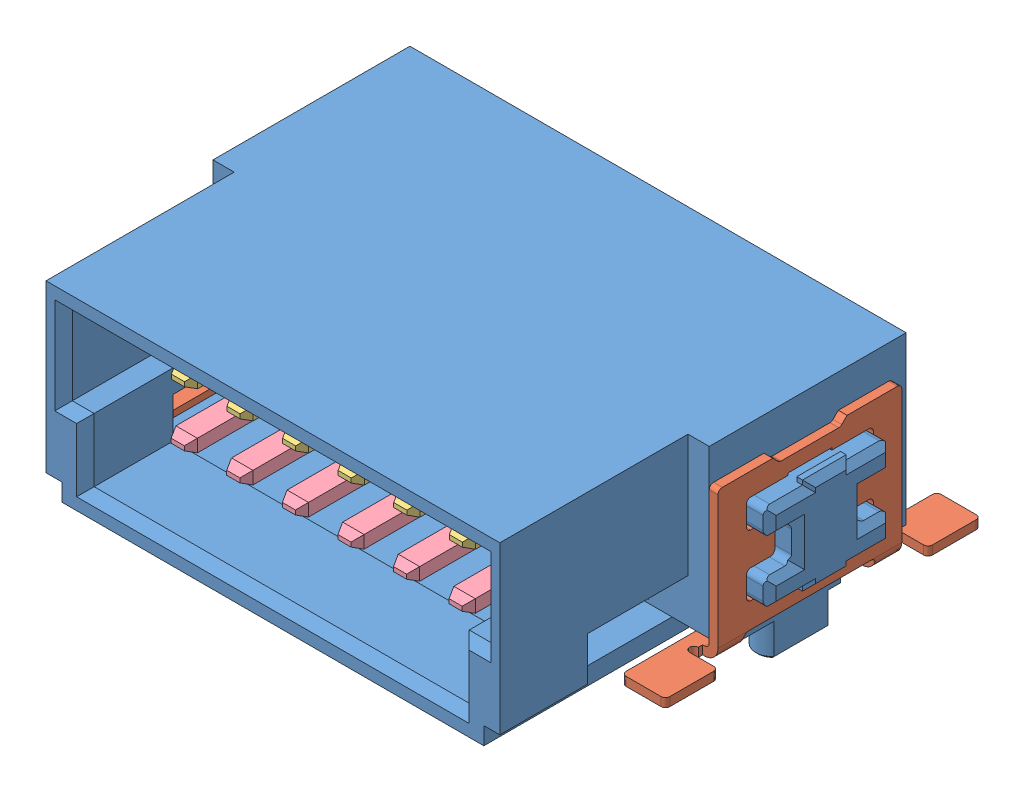
SolidWorks assembly m55-7101242_asm, configuration Default. Lengths in mm.
Overall size (12.7 4.95 10).
16 component instances, 4 part files, 0 mates.
Components (placement in the parent):
- m55-7101242_asm.stp-1: m55-7101242_asm.stp [Default] at origin size (12.7 4.95 10)
  - M55-71012_MOULD.stp-1: M55-71012_MOULD.stp [Default] at origin size (12.7 4.95 8.8)
  - M55-710_STRAP.stp-1: M55-710_STRAP.stp [Default] at (5.67 -2.1 2.4) x (-1 0 0) z (0 0 -1) size (1 3.44 7.2)
  - M55-710_STRAP.stp-2: M55-710_STRAP.stp [Default] at (-5.67 -2.1 2.4) size (1 3.44 7.2)
  - M55-710_LARGE_CONTACT.stp-1: M55-710_LARGE_CONTACT.stp [Default] at (-3.17 0.635 3.6) x (1 0 0) z (0 -1 0) size (1.1 9 2.88)
  - M55-710_LARGE_CONTACT.stp-2: M55-710_LARGE_CONTACT.stp [Default] at (-1.9 0.635 3.6) x (1 0 0) z (0 -1 0) size (1.1 9 2.88)
  - M55-710_LARGE_CONTACT.stp-3: M55-710_LARGE_CONTACT.stp [Default] at (-0.63 0.635 3.6) x (1 0 0) z (0 -1 0) size (1.1 9 2.88)
  - M55-710_LARGE_CONTACT.stp-4: M55-710_LARGE_CONTACT.stp [Default] at (0.64 0.635 3.6) x (1 0 0) z (0 -1 0) size (1.1 9 2.88)
  - M55-710_LARGE_CONTACT.stp-5: M55-710_LARGE_CONTACT.stp [Default] at (1.91 0.635 3.6) x (1 0 0) z (0 -1 0) size (1.1 9 2.88)
  - M55-710_LARGE_CONTACT.stp-6: M55-710_LARGE_CONTACT.stp [Default] at (3.18 0.635 3.6) x (1 0 0) z (0 -1 0) size (1.1 9 2.88)
  - M55-710_SMALL_CONTACT.stp-1: M55-710_SMALL_CONTACT.stp [Default] at (-3.175 -0.635 3.6) x (1 0 0) z (0 -1 0) size (1.1 7.6 1.61)
  - M55-710_SMALL_CONTACT.stp-2: M55-710_SMALL_CONTACT.stp [Default] at (-1.905 -0.635 3.6) x (1 0 0) z (0 -1 0) size (1.1 7.6 1.61)
  - M55-710_SMALL_CONTACT.stp-3: M55-710_SMALL_CONTACT.stp [Default] at (-0.635 -0.635 3.6) x (1 0 0) z (0 -1 0) size (1.1 7.6 1.61)
  - M55-710_SMALL_CONTACT.stp-4: M55-710_SMALL_CONTACT.stp [Default] at (0.635 -0.635 3.6) x (1 0 0) z (0 -1 0) size (1.1 7.6 1.61)
  - M55-710_SMALL_CONTACT.stp-5: M55-710_SMALL_CONTACT.stp [Default] at (1.905 -0.635 3.6) x (1 0 0) z (0 -1 0) size (1.1 7.6 1.61)
  - M55-710_SMALL_CONTACT.stp-6: M55-710_SMALL_CONTACT.stp [Default] at (3.175 -0.635 3.6) x (1 0 0) z (0 -1 0) size (1.1 7.6 1.61)
